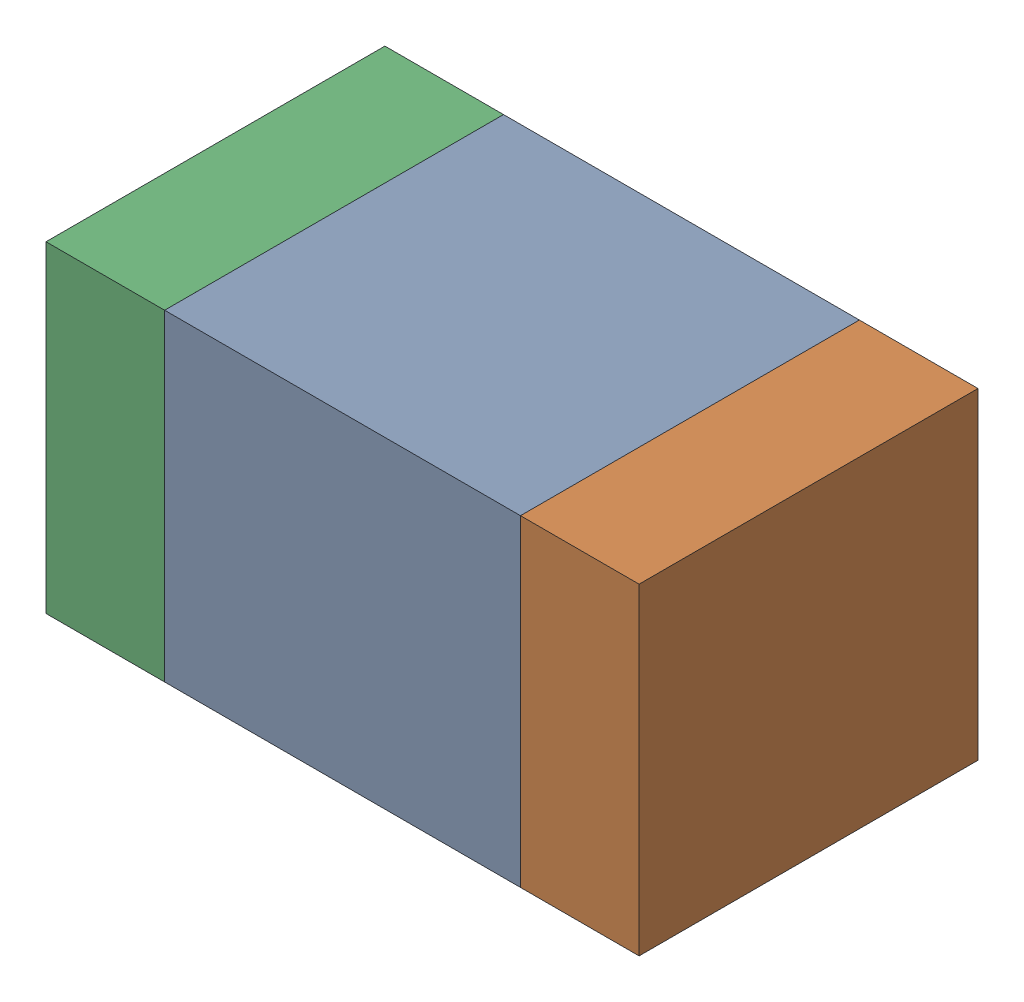
SolidWorks assembly C417PCB, configuration Default. Lengths in mm.
Overall size (1.75 0.95 1).
6 component instances, 2 part files, 0 mates.
Components (placement in the parent):
- 761616112-1: 761616112 [Default] at (118.3 105.8 -2.6638) size (1.05 0.95 1)
  - Extruded_14-1: Extruded_14 [Default] at origin size (1.05 0.95 1)
- 761616248-1: 761616248 [Default] at (119 105.8 -2.6638) size (0.35 0.95 1)
  - Extruded_15-1: Extruded_15 [Default] at origin size (0.35 0.95 1)
- 761616248-2: 761616248 [Default] at (117.6 105.8 -2.6638) size (0.35 0.95 1)
  - Extruded_15-1: Extruded_15 [Default] at origin size (0.35 0.95 1)
